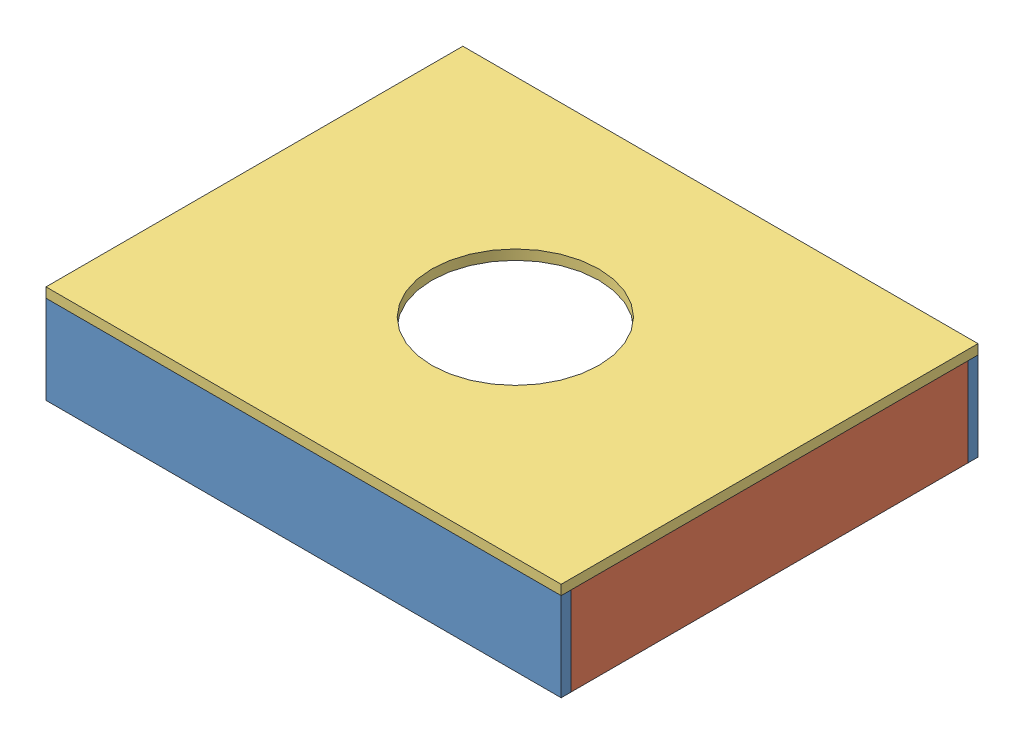
SolidWorks assembly CacheChariotAssemblage, configuration Défaut. Lengths in mm.
Overall size (262 50 212).
6 component instances, 4 part files, 12 mates.
Components (placement in the parent):
- CacheLateral-1: CacheLateral [Défaut] at (-145.0812 10.8242 271.5) size (262 45 5)
- CacheLateral2-1: CacheLateral2 [Défaut] at (-140.0812 55.8242 276.5) x (0 0 1) z (0 -1 0) size (202 5 45)
- CacheLateral-2: CacheLateral [Défaut] at (-145.0812 10.8242 478.5) size (262 45 5)
- CacheLateral2-2: CacheLateral2 [Défaut] at (111.9188 55.8242 478.5) x (0 0 -1) z (0 -1 0) size (202 5 45)
- Pièce3^CacheChariotAssemblage-1: Pièce3^CacheChariotAssemblage [Défaut] at origin (virtual)
- CacheHaut-1: CacheHaut [Défaut] at (116.9188 60.8242 271.5) x (0 0 1) z (0 -1 0) size (212 262 5)
Mates (geometry in assembly coordinates):
- Coïncidente1: coincident: point of CacheLateral-1; point of CacheLateral2-1
- Coïncidente2: coincident: point of CacheLateral-1; point of CacheLateral2-1
- Parallèle1: parallel: plane of CacheLateral-1 through (-145.0812 10.8242 276.5) normal (0 0 1); plane of CacheLateral2-1 through (-140.0812 10.8242 276.5) normal (0 0 -1)
- Coïncidente4: coincident: point of CacheLateral2-1; point of CacheLateral-2
- Coïncidente7: coincident: point of CacheLateral2-1; point of CacheLateral-2
- Parallèle2: parallel: plane of CacheLateral-1 through (-145.0812 10.8242 276.5) normal (0 0 1); plane of CacheLateral-2 through (-145.0812 10.8242 478.5) normal (0 0 -1)
- Coïncidente8: coincident: point of CacheLateral-2; point of CacheLateral2-2
- Coïncidente9: coincident: point of CacheLateral-1; point of CacheLateral2-2
- Parallèle4: parallel: plane of CacheLateral2-1 through (-140.0812 10.8242 276.5) normal (1 0 0); plane of CacheLateral2-2 through (111.9188 10.8242 478.5) normal (-1 0 0)
- Coïncidente14: coincident: point of CacheLateral-1; point of CacheHaut-1
- Coïncidente17: coincident: point of CacheLateral-2; point of CacheHaut-1
- Parallèle5: parallel: plane of CacheLateral2-2 through (111.9188 10.8242 478.5) normal (-1 0 0); plane of CacheHaut-1 through (116.9188 55.8242 271.5) normal (1 0 0)
